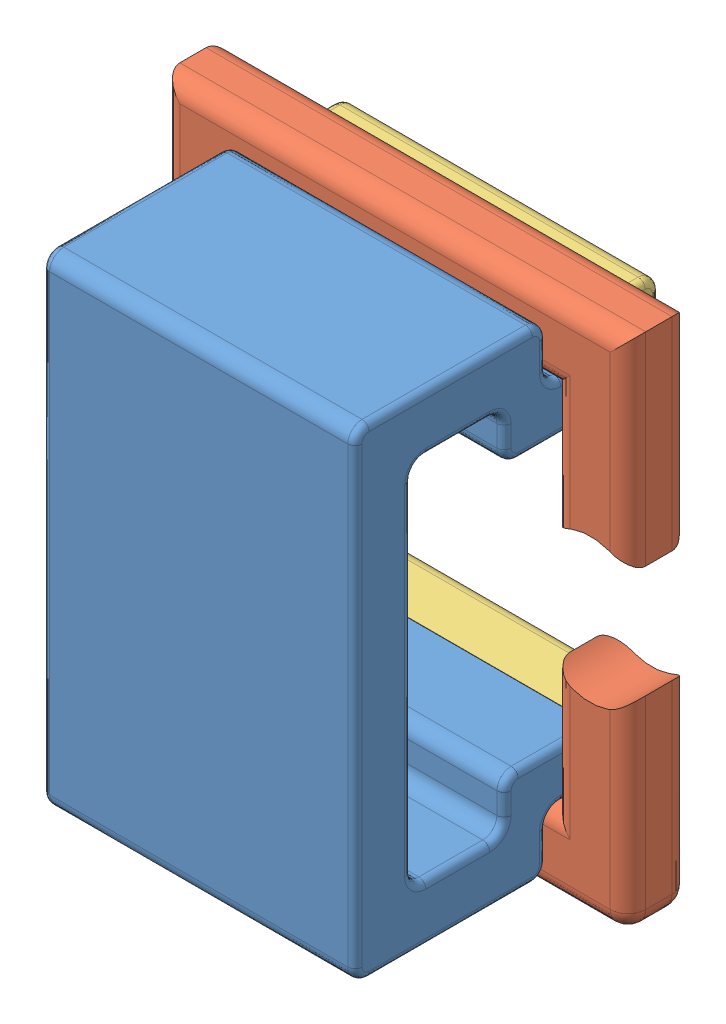
SolidWorks assembly motorAssem_v0, configuration Default. Lengths in mm.
Overall size (32.81 36.48 21.42).
4 component instances, 3 part files, 10 mates.
Components (placement in the parent):
- coilholder_v0-1: coilholder_v0 [Default] at (3.1531 13.3867 33.9588) size (22 33.9 17.02)
- core_v0-1: core_v0 [Default] at (14.2281 13.4267 17.774) x (0 0 1) z (-1 0 0) size (4.35 36.48 32.81)
- coilholderStopper_v0-1: coilholderStopper_v0 [Default] at (3.1781 27.9794 13.001) x (0 0 -1) z (1 0 0) size (6.5 6.5 22)
- coilholderStopper_v0-2: coilholderStopper_v0 [Default] at (25.1781 -1.206 13.001) x (0 0 -1) z (-1 0 0) size (6.5 6.5 22)
Mates (geometry in assembly coordinates):
- Parallel1: parallel: plane of coilholder_v0-1 through (25.1531 26.3367 21.374) normal (0 1 0); plane of core_v0-1 through (3.1531 26.3367 22.199) normal (0 -1 0)
- Coincident6: coincident: plane of coilholder_v0-1 through (25.1531 26.3367 21.374) normal (0 1 0); plane of core_v0-1 through (3.1531 26.3367 22.199) normal (0 -1 0)
- Distance1: distance = 0.25 mm: plane of core_v0-1 through (27.9681 12.0662 22.124) normal (0 0 1); plane of coilholder_v0-1 through (25.1531 29.3367 22.374) normal (0 0 -1)
- Coincident10: coincident: plane of coilholder_v0-1 through (3.1531 23.8367 24.374) normal (-1 0 0); plane of core_v0-1 through (3.1531 26.3367 22.199) normal (1 0 0)
- Distance5: distance = 0.025 mm: plane of coilholder_v0-1 through (23.1531 25.2367 20.9517) normal (-1 0 0); plane of coilholderStopper_v0-1 through (23.1281 25.2617 20.9517) normal (1 0 0)
- Distance3: distance = 0.025 mm: plane of coilholder_v0-1 through (23.1531 25.2367 20.9517) normal (0 -1 0); plane of coilholderStopper_v0-1 through (5.2281 25.2617 20.9517) normal (0 1 0)
- Coincident13: coincident: plane of coilholder_v0-1 through (3.1531 13.3867 20.9517) normal (0 0 -1); plane of coilholderStopper_v0-1 through (3.2031 27.9794 20.9517) normal (0 0 1)
- Distance4: distance = 0.025 mm: plane of coilholder_v0-1 through (23.1531 2.8367 20.9517) normal (-1 0 0); plane of coilholderStopper_v0-2 through (23.1281 1.5117 20.9517) normal (1 0 0)
- Distance2: distance = 0.025 mm: plane of coilholder_v0-1 through (23.1531 1.5367 20.9517) normal (0 1 0); plane of coilholderStopper_v0-2 through (23.1281 1.5117 20.9517) normal (0 -1 0)
- Coincident16: coincident: plane of coilholder_v0-1 through (3.1531 13.3867 20.9517) normal (0 0 -1); plane of coilholderStopper_v0-2 through (25.2031 -1.206 20.9517) normal (0 0 1)
